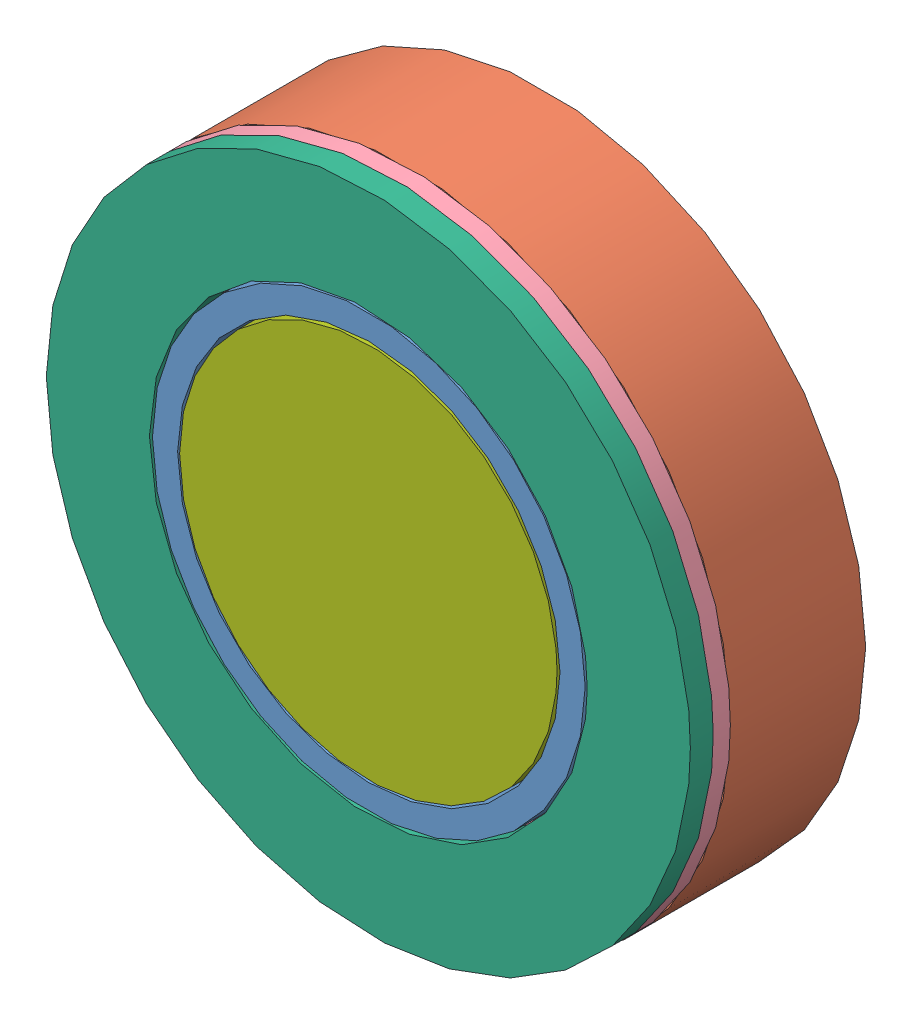
SolidWorks assembly ETA_3, configuration Default. Lengths in mm.
Overall size (256 256 69.7).
7 component instances, 7 part files, 12 mates.
Components (placement in the parent):
- Si_3-2: Si_3 [Default] at (165.1882 108.1192 163.399) size (172 172 69.5)
- B4C_a_m-1: B4C_a_m [Default] at (165.1882 108.1192 163.399) size (256 256 53.8)
- B4C_b_m-1: B4C_b_m [Default] at (165.1882 108.1192 163.399) size (150 150 53.8)
- Ba_a_m-1: Ba_a_m [Default] at (165.1882 108.1192 217.199) size (256 256 6.8)
- Ba_b_m-1: Ba_b_m [Default] at (165.1882 108.1192 217.199) size (150 150 6.8)
- Bi_4a_m-1: Bi_4a_m [Default] at (165.1882 108.1192 223.999) size (256 256 9.1)
- Bi_4b_m-1: Bi_4b_m [Default] at (165.1882 108.1192 223.999) size (150 150 9.1)
Mates (geometry in assembly coordinates):
- Coincident41: coincident aligned: plane of Si_3-2 through (165.1882 108.1192 163.399) normal (0 0 -1); plane of B4C_a_m-1 through (165.1882 108.1192 163.399) normal (0 0 -1)
- Coincident42: coincident aligned: plane of Si_3-2 through (165.1882 108.1192 163.399) normal (0 0 -1); plane of B4C_b_m-1 through (165.1882 108.1192 163.399) normal (0 0 -1)
- Concentric1: concentric aligned: circle of Si_3-2; circle of B4C_b_m-1
- Concentric3: concentric aligned: circle of Si_3-2; circle of B4C_a_m-1
- Coincident43: coincident anti-aligned: plane of B4C_a_m-1 through (165.1882 108.1192 217.199) normal (0 0 1); plane of Ba_a_m-1 through (165.1882 108.1192 217.199) normal (0 0 -1)
- Coincident44: coincident anti-aligned: plane of B4C_b_m-1 through (165.1882 108.1192 217.199) normal (0 0 1); plane of Ba_b_m-1 through (165.1882 108.1192 217.199) normal (0 0 -1)
- Coincident45: coincident aligned: circle of B4C_b_m-1; circle of Ba_b_m-1
- Coincident46: coincident aligned: circle of B4C_a_m-1; circle of Ba_a_m-1
- Coincident47: coincident anti-aligned: plane of Ba_a_m-1 through (165.1882 108.1192 223.999) normal (0 0 1); plane of Bi_4a_m-1 through (165.1882 108.1192 223.999) normal (0 0 -1)
- Coincident48: coincident anti-aligned: plane of Ba_b_m-1 through (165.1882 108.1192 223.999) normal (0 0 1); plane of Bi_4b_m-1 through (165.1882 108.1192 223.999) normal (0 0 -1)
- Coincident49: coincident aligned: circle of Ba_a_m-1; circle of Bi_4a_m-1
- Coincident50: coincident aligned: circle of Ba_b_m-1; circle of Bi_4b_m-1
